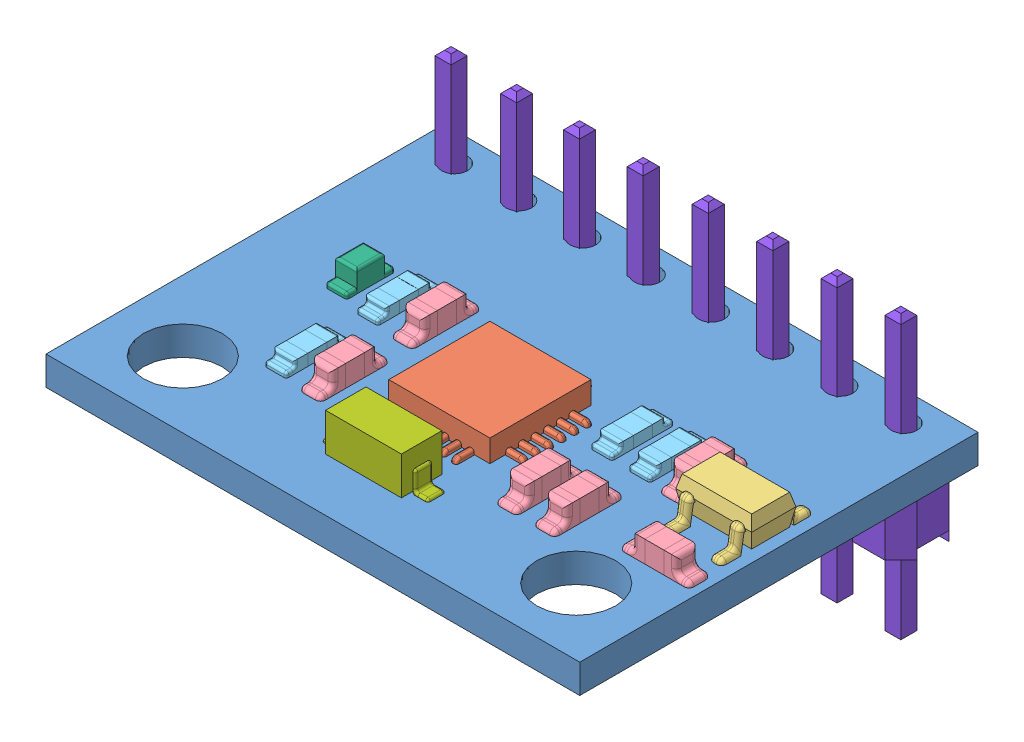
SolidWorks assembly MPU 6050 IMU, configuration Default. Lengths in mm.
Overall size (21.11 11.18 15.75).
23 component instances, 8 part files, 49 mates.
Components (placement in the parent):
- Base-1: Base [Default] at (7.1889 11.4305 16.8035) size (21.11 1.14 15.75)
- sensor chip-1: sensor chip [Default] at (7.1889 12.022 17.6775) size (5.4 0.9 5.4)
- S2NH chip-1: S2NH chip [Default] at (16.0426 12.852 16.8035) size (3 1.35 3.65)
- Resistor small-3: Resistor small [Default] at (16.0426 12.0036 19.6035) size (2.75 0.99 1)
- Resistor small-4: Resistor small [Default] at (13.9176 12.0036 15.9285) x (0 0 -1) z (1 0 0) size (2.75 0.99 1)
- Resistor small black-3: Resistor small black [Default] at (12.5676 12.002 15.9285) x (0 0 1) z (-1 0 0) size (2.45 0.6 1.02)
- Resistor small black-4: Resistor small black [Default] at (11.0676 12.002 15.9285) x (0 0 1) z (-1 0 0) size (2.45 0.6 1.02)
- Resistor small-5: Resistor small [Default] at (12.5676 12.0036 19.5525) x (0 0 -1) z (1 0 0) size (2.75 0.99 1)
- Resistor small-6: Resistor small [Default] at (11.0676 12.0036 19.5525) x (0 0 -1) z (1 0 0) size (2.75 0.99 1)
- Resistor small-7: Resistor small [Default] at (3.3102 12.0036 19.5525) x (0 0 -1) z (1 0 0) size (2.75 0.99 1)
- Resistor small black-5: Resistor small black [Default] at (1.8102 12.002 15.9281) x (0 0 -1) z (1 0 0) size (2.45 0.6 1.02)
- Resistor small-8: Resistor small [Default] at (3.3102 12.0036 15.9285) x (0 0 1) z (-1 0 0) size (2.75 0.99 1)
- Small LED-1: Small LED [Default] at (0.3052 12.002 15.9285) size (0.85 0.84 1.9)
- Resistor small black-6: Resistor small black [Default] at (1.8102 12.002 19.5525) x (0 0 1) z (-1 0 0) size (2.45 0.6 1.02)
- Resistor black-1: Resistor black [Default] at (7.1889 12.852 21.8775) size (4.2 1.6 1.6)
- pin header-9: pin header [Default] at (15.9605 8.319 10.1995) size (2.54 11.18 2.54)
- pin header-10: pin header [Default] at (13.4413 8.319 10.1995) size (2.54 11.18 2.54)
- pin header-11: pin header [Default] at (0.7686 8.319 10.1995) size (2.54 11.18 2.54)
- pin header-12: pin header [Default] at (8.3455 8.319 10.1995) size (2.54 11.18 2.54)
- pin header-13: pin header [Default] at (5.7737 8.319 10.1995) size (2.54 11.18 2.54)
- pin header-14: pin header [Default] at (-1.8239 8.319 10.1995) size (2.54 11.18 2.54)
- pin header-15: pin header [Default] at (3.2549 8.319 10.1995) size (2.54 11.18 2.54)
- pin header-16: pin header [Default] at (10.8964 8.319 10.1995) size (2.54 11.18 2.54)
Mates (geometry in assembly coordinates):
- Concentric1: concentric: cylinder of Base-1 through (15.9646 12.002 10.0725) axis (0 -1 0) radius 0.508; point of pin header-1
- Coincident4: coincident anti-aligned: plane of Base-1 through (7.1889 10.859 16.8035) normal (0 -1 0); plane of pin header-1 through (15.9646 10.859 10.0725) normal (0 1 0)
- Parallel1: parallel aligned: plane of Base-1 through (17.7426 12.002 24.6775) normal (1 0 0); plane of pin header-1 through (17.2346 8.319 10.7075) normal (1 0 0)
- Coincident6: coincident anti-aligned: plane of Base-1 through (7.1889 12.002 16.8035) normal (0 1 0); plane of sensor chip-1 through (7.1889 12.002 17.6775) normal (0 -1 0)
- Coincident7: coincident aligned: plane of Base-1 through (7.1889 11.4305 16.8035) normal (1 0 0); plane of sensor chip-1 through (7.1889 12.022 17.6775) normal (1 0 0)
- Distance1: distance = 5 mm aligned: plane of sensor chip-1 through (5.1889 12.902 19.6775) normal (0 0 1); plane of Base-1 through (-3.3648 12.002 24.6775) normal (0 0 1)
- Coincident8: coincident anti-aligned: plane of Base-1 through (7.1889 12.002 16.8035) normal (0 1 0); plane of S2NH chip-1 through (16.0426 12.002 16.8035) normal (0 -1 0)
- Coincident9: coincident aligned: plane of Base-1 through (7.1889 11.4305 16.8035) normal (0 0 1); plane of S2NH chip-1 through (16.0426 12.852 16.8035) normal (0 0 1)
- Distance2: distance = 0.2 mm: line of S2NH chip-1 through (17.5426 12.852 17.6785) axis (0 0 -1); plane of Base-1 through (17.7426 12.002 24.6775) normal (1 0 0)
- Coincident19: coincident anti-aligned: plane of Base-1 through (7.1889 12.002 16.8035) normal (0 1 0); plane of Resistor small-3 through (16.9176 12.002 20.0335) normal (0 -1 0)
- Coincident20: coincident aligned: plane of S2NH chip-1 through (16.0426 12.852 16.8035) normal (1 0 0); plane of Resistor small-3 through (16.0426 12.0036 19.6035) normal (1 0 0)
- Distance5: distance = 1.5 mm: line of S2NH chip-1 through (15.2658 12.852 17.6785) axis (1 0 0); plane of Resistor small-3 through (16.4176 12.0036 19.1785) normal (0 0 -1)
- Coincident22: coincident anti-aligned: plane of Base-1 through (7.1889 12.002 16.8035) normal (0 1 0); plane of Resistor small-4 through (14.3476 12.002 15.0535) normal (0 -1 0)
- Coincident24: coincident: line of S2NH chip-1 through (16.8194 12.852 15.9285) axis (-1 0 0); plane of Resistor small-4 through (13.9176 12.0036 15.9285) normal (0 0 -1)
- Distance6: distance = 0.2 mm: plane of Resistor small-4 through (14.3426 12.0036 15.5535) normal (1 0 0); line of S2NH chip-1 through (14.5426 12.852 15.9285) axis (0 0 1)
- Coincident26: coincident anti-aligned: plane of Base-1 through (7.1889 12.002 16.8035) normal (0 1 0); plane of Resistor small black-3 through (12.1426 12.002 16.3035) normal (0 -1 0)
- Coincident28: coincident anti-aligned: plane of Resistor small-4 through (13.9176 12.0036 15.9285) normal (0 0 -1); plane of Resistor small black-3 through (12.5676 12.002 15.9285) normal (0 0 1)
- Distance7: distance = 0.5 mm anti-aligned: plane of Resistor small-4 through (13.4926 12.0036 15.5535) normal (-1 0 0); plane of Resistor small black-3 through (12.9926 12.002 16.3035) normal (1 0 0)
- Coincident30: coincident anti-aligned: plane of Base-1 through (7.1889 12.002 16.8035) normal (0 1 0); plane of Resistor small-5 through (12.9976 12.002 18.6775) normal (0 -1 0)
- Coincident31: coincident anti-aligned: plane of Resistor small black-3 through (12.5676 12.002 15.9285) normal (-1 0 0); plane of Resistor small-5 through (12.5676 12.0036 19.5525) normal (1 0 0)
- Distance8: distance = 4.25 mm aligned: plane of Resistor small-5 through (12.5676 12.0036 20.4275) normal (0 0 1); plane of Base-1 through (-3.3648 12.002 24.6775) normal (0 0 1)
- Coincident33: coincident anti-aligned: plane of Base-1 through (7.1889 12.002 16.8035) normal (0 1 0); plane of Resistor small-8 through (2.8802 12.002 15.0535) normal (0 -1 0)
- Coincident34: coincident anti-aligned: plane of Resistor small-7 through (3.3102 12.0036 19.5525) normal (1 0 0); plane of Resistor small-8 through (3.3102 12.0036 15.9285) normal (-1 0 0)
- Coincident36: coincident: line of S2NH chip-1 through (15.8194 12.852 15.9285) axis (-1 0 0); plane of Resistor small-8 through (3.3102 12.0036 15.9285) normal (0 0 1)
- Coincident37: coincident anti-aligned: plane of Base-1 through (7.1889 12.002 16.8035) normal (0 1 0); plane of Small LED-1 through (0.3052 12.002 15.9285) normal (0 -1 0)
- Coincident38: coincident: line of S2NH chip-1 through (15.8194 12.852 15.9285) axis (-1 0 0); plane of Small LED-1 through (0.3052 12.002 15.9285) normal (0 0 1)
- Distance9: distance = 1.5 mm aligned: plane of Small LED-1 through (-0.1148 12.842 16.4785) normal (-1 0 0); plane of Resistor small black-5 through (1.3852 12.002 15.5531) normal (-1 0 0)
- Coincident40: coincident anti-aligned: plane of Base-1 through (7.1889 12.002 16.8035) normal (0 1 0); plane of Resistor small black-6 through (1.3852 12.002 19.9275) normal (0 -1 0)
- Coincident41: coincident anti-aligned: plane of Resistor small black-5 through (1.8102 12.002 15.9281) normal (1 0 0); plane of Resistor small black-6 through (1.8102 12.002 19.5525) normal (-1 0 0)
- Coincident42: coincident anti-aligned: plane of Resistor small-7 through (3.3102 12.0036 19.5525) normal (0 0 -1); plane of Resistor small black-6 through (1.8102 12.002 19.5525) normal (0 0 1)
- Coincident43: coincident anti-aligned: plane of Base-1 through (7.1889 12.002 16.8035) normal (0 1 0); plane of Resistor black-1 through (5.5889 12.002 22.2275) normal (0 -1 0)
- Coincident44: coincident aligned: plane of Base-1 through (7.1889 11.4305 16.8035) normal (1 0 0); plane of Resistor black-1 through (7.1889 12.852 21.8775) normal (1 0 0)
- Distance10: distance = 2 mm aligned: plane of Resistor black-1 through (5.6889 13.602 22.6775) normal (0 0 1); plane of Base-1 through (-3.3648 12.002 24.6775) normal (0 0 1)
- Coincident48: coincident: plane of Base-1 through (7.1889 10.859 16.8035) normal (0 -1 0); plane of pin header-15 through (3.2549 10.859 10.3705) normal (0 1 0)
- Coincident49: coincident: plane of Base-1 through (7.1889 10.859 16.8035) normal (0 -1 0); plane of pin header-13 through (5.7737 10.859 10.2617) normal (0 1 0)
- Coincident50: coincident: plane of Base-1 through (7.1889 10.859 16.8035) normal (0 -1 0); plane of pin header-14 through (-1.8239 10.859 10.0701) normal (0 1 0)
- Coincident51: coincident: plane of Base-1 through (7.1889 10.859 16.8035) normal (0 -1 0); plane of pin header-12 through (8.3455 10.859 9.9188) normal (0 1 0)
- Coincident52: coincident: plane of Base-1 through (7.1889 10.859 16.8035) normal (0 -1 0); plane of pin header-16 through (10.8964 10.859 10.1981) normal (0 1 0)
- Coincident53: coincident: plane of Base-1 through (7.1889 10.859 16.8035) normal (0 -1 0); plane of pin header-11 through (0.7686 10.859 10.0379) normal (0 1 0)
- Coincident54: coincident: plane of Base-1 through (7.1889 10.859 16.8035) normal (0 -1 0); plane of pin header-10 through (13.4413 10.859 10.1304) normal (0 1 0)
- Coincident55: coincident: plane of Base-1 through (7.1889 10.859 16.8035) normal (0 -1 0); plane of pin header-9 through (15.9605 10.859 10.1661) normal (0 1 0)
- Coincident56: coincident aligned: plane of Base-1 through (-3.3648 12.002 8.9295) normal (0 0 -1); plane of pin header-14 through (-2.4589 10.859 8.9295) normal (0 0 -1)
- Coincident57: coincident aligned: plane of Base-1 through (-3.3648 12.002 8.9295) normal (0 0 -1); plane of pin header-11 through (0.1336 10.859 8.9295) normal (0 0 -1)
- Coincident58: coincident aligned: plane of Base-1 through (-3.3648 12.002 8.9295) normal (0 0 -1); plane of pin header-15 through (2.6199 10.859 8.9295) normal (0 0 -1)
- Coincident59: coincident aligned: plane of Base-1 through (-3.3648 12.002 8.9295) normal (0 0 -1); plane of pin header-13 through (5.1387 10.859 8.9295) normal (0 0 -1)
- Coincident60: coincident aligned: plane of Base-1 through (-3.3648 12.002 8.9295) normal (0 0 -1); plane of pin header-12 through (7.7105 10.859 8.9295) normal (0 0 -1)
- Coincident61: coincident aligned: plane of Base-1 through (-3.3648 12.002 8.9295) normal (0 0 -1); plane of pin header-16 through (10.2614 10.859 8.9295) normal (0 0 -1)
- Coincident62: coincident aligned: plane of Base-1 through (-3.3648 12.002 8.9295) normal (0 0 -1); plane of pin header-10 through (12.8063 10.859 8.9295) normal (0 0 -1)
- Coincident63: coincident aligned: plane of Base-1 through (-3.3648 12.002 8.9295) normal (0 0 -1); plane of pin header-9 through (15.3255 10.859 8.9295) normal (0 0 -1)
